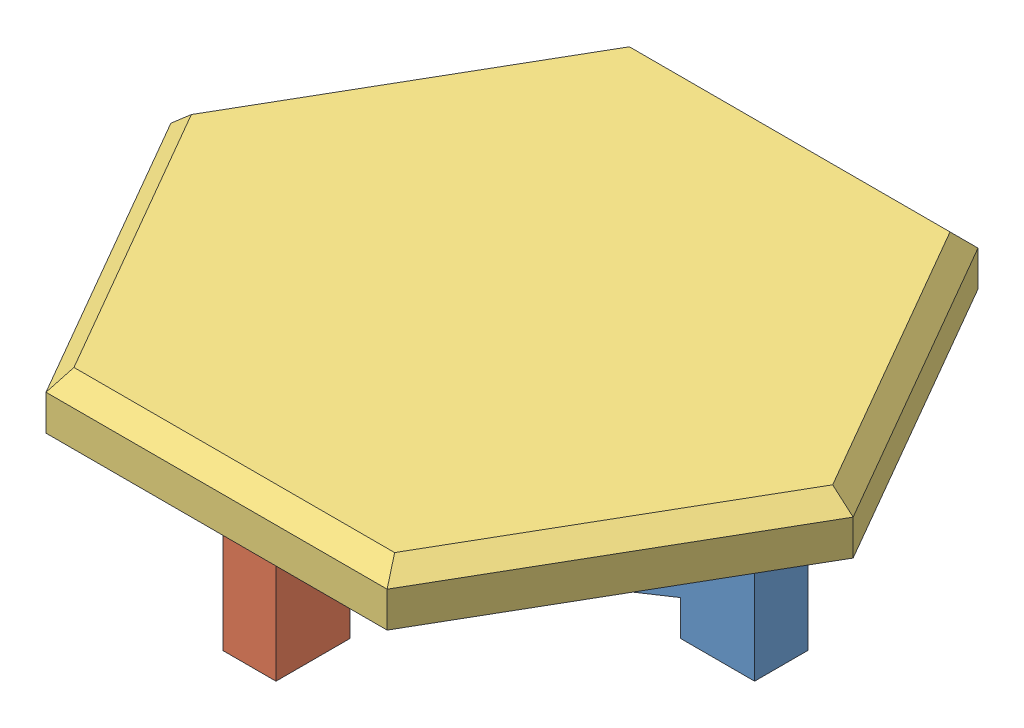
SolidWorks assembly Assem1, configuration Default. Lengths in mm.
Overall size (230.94 62 200).
3 component instances, 3 part files, 4 mates.
Components (placement in the parent):
- Leg1-1: Leg1 [Default] at (3.1876 -4.5988 1.4423) size (180 44 18)
- Leg2-1: Leg2 [Default] at (3.1876 -4.5988 1.4423) x (0 0 -1) z (1 0 0) size (180 44 18)
- Base-1: Base [Default] at (2.2845 26.4012 1.6525) size (230.94 18 200)
Mates (geometry in assembly coordinates):
- Coincident1: coincident: plane of Leg1-1 through (-5.8124 -4.5988 -7.5577) normal (0 1 0); plane of Leg2-1 through (-5.8124 -4.5988 10.4423) normal (0 -1 0)
- Perpendicular1: perpendicular: plane of Leg1-1 through (-86.8124 17.4012 -7.5577) normal (0 0 -1); plane of Leg2-1 through (12.1876 17.4012 91.4423) normal (1 0 0)
- Coincident3: coincident aligned: line of Leg1-1 through (12.1876 -4.5988 -7.5577) axis (0 1 0); line of Leg2-1 through (12.1876 -26.5988 -7.5577) axis (0 1 0)
- Coincident4: coincident anti-aligned: plane of Leg2-1 through (12.1876 17.4012 -88.5577) normal (0 1 0); plane of Base-1 through (60.0196 17.4012 -98.3475) normal (0 -1 0)
